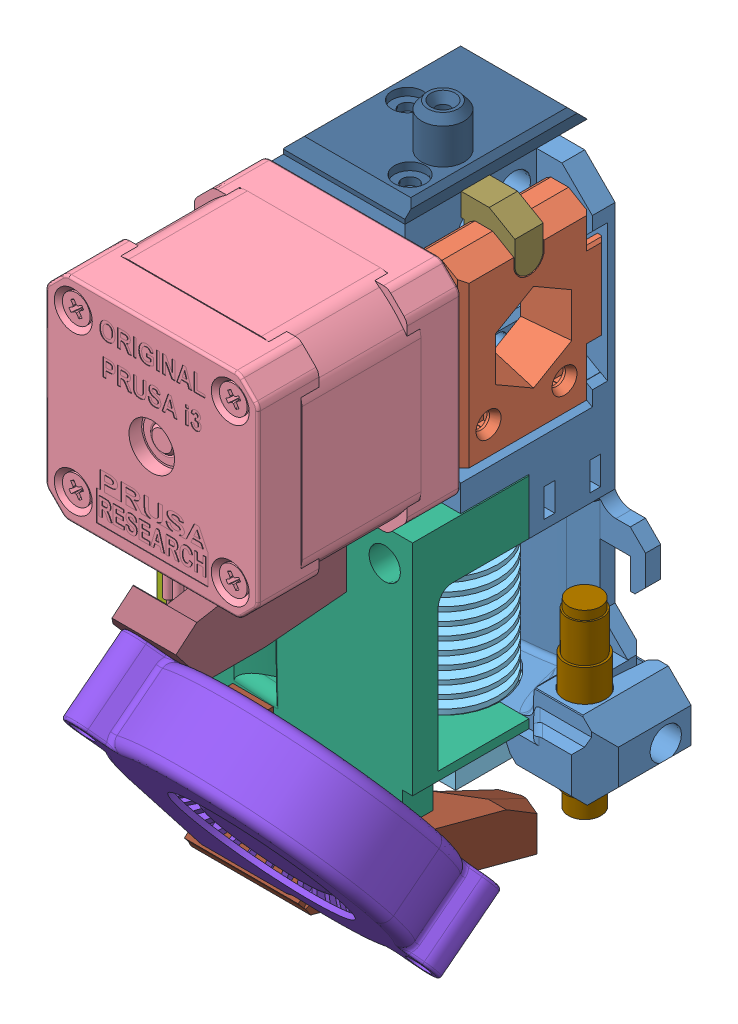
SolidWorks assembly Extruder Assembly, configuration Default. Lengths in mm.
Overall size (76.26 114.7 92.58).
13 component instances, 13 part files, 34 mates.
Components (placement in the parent):
- extruder-body(R3)-1: extruder-body(R3) [Default] at (70.8414 -115.0738 -111.886) size (63.5 95 30.5)
- extruder-idler(R2)-1: extruder-idler(R2) [Default] at (-144.6524 7.4262 -113.386) x (0 0 1) z (-1 0 0) size (28 34 17)
- idler pulley shaft-1: idler pulley shaft [Default] at (-140.6524 34.4262 -110.636) size (3 3 24)
- NEMA-17 40mm PR-1: NEMA-17 40mm PR [По умолчанию] at (-148.6524 34.4262 -41.386) x (-1 0 0) z (0 -1 0) size (42.3 62 51.35)
- E3D V6-1: E3D V6 [Default] at (-144.6524 -2.6738 -94.886) x (1 0 0) z (0 -1 0) size (21.69 25.84 58.6)
- extruder-cover(R3)-1: extruder-cover(R3) [Default] at (-363.5774 -115.0738 -71.886) x (-1 0 0) z (0 0 -1) size (49.56 50.02 24.29)
- Noctua-NF-A4x10-1: Noctua-NF-A4x10 [Default] at (-172.6515 -13.1393 -91.9515) x (0 -1 0) z (-1 0 0) size (40.06 40.06 12.26)
- FAN_5015_BLOWER-1: FAN_5015_BLOWER [Default] at (-127.1524 -24.9721 -41.5481) x (0 -0.788011 -0.615661) z (1 0 0) size (51.75 17.19 52.1)
- PINDA Probe-1: PINDA Probe [Default] at (-121.6524 -18.3076 -99.886) x (-0.993832 0 -0.110899) z (0 -1 0) size (7.8 7.8 35.75)
- filament-sensor-cover-1: filament-sensor-cover [Default] at (-144.6524 7.4262 -111.886) x (-1 0 0) z (0 0 -1) size (24 11.5 36)
- nozzle-fan(R3)-1: nozzle-fan(R3) [Default] at (-144.6524 7.4262 -106.886) x (-1 0 0) z (0 1 0) size (47.5 38.79 17)
- extruder-idler-plug-1: extruder-idler-plug [Default] at (-144.6524 7.4262 -113.386) x (-1 0 0) z (0 0 -1) size (10.6 10.3 5.6)
- nozzle-fan-holder(R3)-1: nozzle-fan-holder(R3) [Default] at (-144.6524 5.9262 -107.386) x (-1 0 0) z (0 1 0) size (15.6 33.75 14)
Mates (geometry in assembly coordinates):
- Concentric1: concentric aligned: cylinder of extruder-idler(R2)-1 through (-140.6524 34.4262 -81.386) axis (0 0 -1) radius 1.45; cylinder of idler pulley shaft-1 through (-140.6524 34.4262 -86.636) axis (0 0 -1) radius 1.5
- Coincident1: coincident aligned: plane of extruder-idler(R2)-1 through (-151.6524 34.4262 -86.636) normal (0 0 1); plane of idler pulley shaft-1 through (-140.6524 34.4262 -86.636) normal (0 0 1)
- Coincident11: coincident aligned: plane of E3D V6-1 through (-144.6524 -42.8738 -94.886) normal (0 -1 0); plane of PINDA Probe-1 through (-121.6524 -42.8738 -99.886) normal (0 -1 0)
- Concentric18: concentric: cylinder of extruder-idler(R2)-1 through (-124.6524 50.4262 -94.886) axis (-1 0 0) radius 3; cylinder of extruder-idler-plug-1 through (-118.0971 50.4262 -94.886) axis (-1 0 0) radius 2.8
- Concentric19: concentric anti-aligned: cylinder of extruder-idler(R2)-1 through (-133.1524 49.9262 -81.386) axis (0 0 -1) radius 1.65; cylinder of NEMA-17 40mm PR-1 through (-133.1524 49.9262 -81.386) axis (0 0 1) radius 1.25
- Concentric20: concentric aligned: cylinder of extruder-body(R3)-1 through (-164.1524 49.9262 -71.886) axis (0 0 -1) radius 1.65; circle of NEMA-17 40mm PR-1
- Concentric21: concentric aligned: circle of extruder-body(R3)-1; cylinder of NEMA-17 40mm PR-1 through (-133.1524 49.9262 -81.386) axis (0 0 1) radius 1.25
- Coincident13: coincident aligned: plane of extruder-body(R3)-1 through (70.8414 -115.0738 -94.386) normal (0 0 1); plane of extruder-idler(R2)-1 through (-144.6524 7.4262 -94.386) normal (0 0 1)
- Coincident14: coincident anti-aligned: plane of extruder-body(R3)-1 through (-127.6524 -29.0738 -81.386) normal (0 0 1); plane of NEMA-17 40mm PR-1 through (-148.6524 34.4262 -81.386) normal (0 0 -1)
- Concentric22: concentric aligned: cone of extruder-body(R3)-1 through (-156.6524 57.4262 -99.886) axis (0 -1 0); cylinder of filament-sensor-cover-1 through (-156.6524 67.4262 -99.886) axis (0 -1 0) radius 1.6
- Concentric23: concentric aligned: circle of extruder-body(R3)-1; circle of filament-sensor-cover-1
- Coincident15: coincident anti-aligned: plane of extruder-body(R3)-1 through (-127.6524 57.4262 -81.386) normal (0 1 0); plane of filament-sensor-cover-1 through (-138.6524 57.4262 -81.386) normal (0 -1 0)
- Concentric24: concentric aligned: cylinder of E3D V6-1 through (-144.6524 -2.6738 -94.886) axis (0 -1 0) radius 5.95; cylinder of extruder-cover(R3)-1 through (-144.6524 11.4262 -94.886) axis (0 -1 0) radius 6.15
- Parallel1: parallel aligned: plane of E3D V6-1 through (-137.1524 -42.8738 -89.886) normal (1 0 0); plane of extruder-cover(R3)-1 through (-127.6524 -29.0738 -71.886) normal (1 0 0)
- Coincident16: coincident anti-aligned: plane of E3D V6-1 through (-152.5524 4.0262 -94.886) normal (0 1 0); plane of extruder-cover(R3)-1 through (-144.6524 4.0262 -94.886) normal (0 -1 0)
- Concentric25: concentric aligned: cylinder of extruder-body(R3)-1 through (-133.1524 6.9262 -76.886) axis (0 0 -1) radius 1.65; cylinder of extruder-cover(R3)-1 through (-133.1524 6.9262 -68.886) axis (0 0 -1) radius 1.65
- Concentric26: concentric aligned: cylinder of extruder-body(R3)-1 through (-161.6524 10.4262 -86.886) axis (0 0 -1) radius 1.7; circle of extruder-cover(R3)-1
- Coincident17: coincident anti-aligned: plane of extruder-body(R3)-1 through (-126.6524 -31.5738 -94.886) normal (0 0 1); plane of extruder-cover(R3)-1 through (-127.6524 -29.0738 -94.886) normal (0 0 -1)
- Concentric27: concentric anti-aligned: cylinder of extruder-cover(R3)-1 through (-164.6524 2.9262 -75.886) axis (-1 0 0) radius 1.4; cylinder of Noctua-NF-A4x10-1 through (-178.1506 2.9262 -75.886) axis (1 0 0) radius 2.159
- Parallel2: parallel aligned: plane of extruder-cover(R3)-1 through (-127.6524 -29.0738 -71.886) normal (0 0 1); plane of Noctua-NF-A4x10-1 through (-178.1506 4.8886 -71.9236) normal (0 0 1)
- Coincident18: coincident anti-aligned: plane of extruder-cover(R3)-1 through (-167.1524 -30.0738 -70.886) normal (-1 0 0); plane of Noctua-NF-A4x10-1 through (-167.1524 -31.1672 -73.9236) normal (1 0 0)
- Concentric29: concentric anti-aligned: cylinder of extruder-body(R3)-1 through (-121.6524 2.4262 -99.886) axis (0 -1 0) radius 4.05; cylinder of PINDA Probe-1 through (-121.6524 -4.2886 -99.886) axis (0 1 0) radius 3.9
- Concentric30: concentric aligned: cylinder of extruder-cover(R3)-1 through (-159.1524 -33.0738 -69.886) axis (0 0 -1) radius 1.4; cylinder of nozzle-fan(R3)-1 through (-159.1524 -33.0738 -61.886) axis (0 0 -1) radius 1.6
- Coincident19: coincident anti-aligned: plane of extruder-cover(R3)-1 through (-127.6524 -29.0738 -71.886) normal (0 0 1); plane of nozzle-fan(R3)-1 through (-119.6524 -36.5738 -71.886) normal (0 0 -1)
- Parallel3: parallel aligned: plane of extruder-cover(R3)-1 through (-167.1524 -30.0738 -70.886) normal (-1 0 0); plane of nozzle-fan(R3)-1 through (-163.1524 -45.5738 -71.886) normal (-1 0 0)
- Concentric31: concentric aligned: cylinder of extruder-cover(R3)-1 through (-150.1524 6.9262 -71.886) axis (0 0 -1) radius 1.65; cylinder of nozzle-fan-holder(R3)-1 through (-150.1524 6.9262 -65.386) axis (0 0 -1) radius 1.6
- Coincident23: coincident anti-aligned: plane of extruder-cover(R3)-1 through (-127.6524 -29.0738 -71.886) normal (0 0 1); plane of nozzle-fan-holder(R3)-1 through (-140.6524 -19.0738 -71.886) normal (0 0 -1)
- Parallel4: parallel aligned: plane of extruder-cover(R3)-1 through (-176.1524 5.9262 -71.886) normal (-1 0 0); plane of nozzle-fan-holder(R3)-1 through (-155.6524 -19.0738 -71.886) normal (-1 0 0)
- Coincident24: coincident: plane of FAN_5015_BLOWER-1 through (-127.1524 -15.4909 -53.6834) normal (0 0.615661 -0.788011); plane of nozzle-fan-holder(R3)-1 through (-119.6524 -39.8389 -72.7062) normal (0 -0.615661 0.788011)
- Parallel6: parallel: plane of extruder-cover(R3)-1 through (-176.1524 5.9262 -71.886) normal (-1 0 0); plane of FAN_5015_BLOWER-1 through (-154.7524 -45.224 -57.3706) normal (-1 0 0)
- Coincident25: coincident: point of FAN_5015_BLOWER-1; point of nozzle-fan-holder(R3)-1
- Parallel8: parallel: plane of filament-sensor-cover-1 through (-138.6524 57.4262 -81.386) normal (0 0 1); plane of extruder-idler-plug-1 through (-118.0971 50.4262 -92.086) normal (0 0 1)
- Parallel9: parallel aligned: plane of extruder-body(R3)-1 through (-127.6524 -14.5738 -106.9486) normal (1 0 0); plane of extruder-idler(R2)-1 through (-127.6524 19.4262 -81.886) normal (1 0 0)
- Concentric38: concentric aligned: cylinder of extruder-idler(R2)-1 through (-133.1524 49.9262 -81.386) axis (0 0 -1) radius 1.65; cylinder of extruder-idler-plug-1 through (-133.1524 49.9262 -81.386) axis (0 0 -1) radius 1.5
